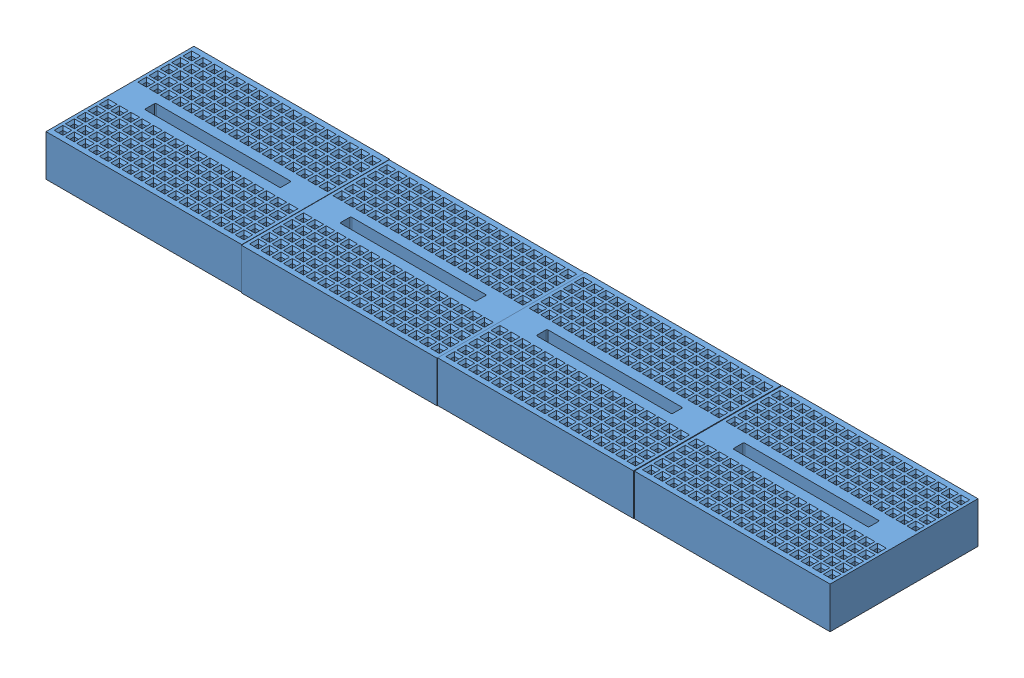
SolidWorks assembly Assem1, configuration Default. Lengths in mm.
Overall size (180 9.71 34.34).
4 component instances, 1 part files, 3 mates.
Components (placement in the parent):
- MINIPROTOBOARD-1: MINIPROTOBOARD [Default] at (27.1001 14.4376 32.0233) size (45 9.5 34)
- MINIPROTOBOARD-2: MINIPROTOBOARD [Default] at (72.1001 14.3685 32.1136) size (45 9.5 34)
- MINIPROTOBOARD-3: MINIPROTOBOARD [Default] at (162.1001 14.231 31.7752) size (45 9.5 34)
- MINIPROTOBOARD-4: MINIPROTOBOARD [Default] at (117.1001 14.3838 31.9917) size (45 9.5 34)
Mates (geometry in assembly coordinates):
- Coincident2: coincident: plane of assembly; plane of assembly; plane of MINIPROTOBOARD-1 through (49.6001 23.9376 49.0233) normal (1 0 0); plane of MINIPROTOBOARD-2 through (49.6001 23.8685 49.1136) normal (-1 0 0)
- Coincident3: coincident: plane of assembly; plane of assembly; plane of MINIPROTOBOARD-2 through (94.6001 23.8685 49.1136) normal (1 0 0); plane of MINIPROTOBOARD-4 through (94.6001 23.8838 48.9917) normal (-1 0 0)
- Coincident4: coincident: plane of assembly; plane of assembly; plane of MINIPROTOBOARD-3 through (139.6001 23.731 48.7752) normal (-1 0 0); plane of MINIPROTOBOARD-4 through (139.6001 23.8838 48.9917) normal (1 0 0)
